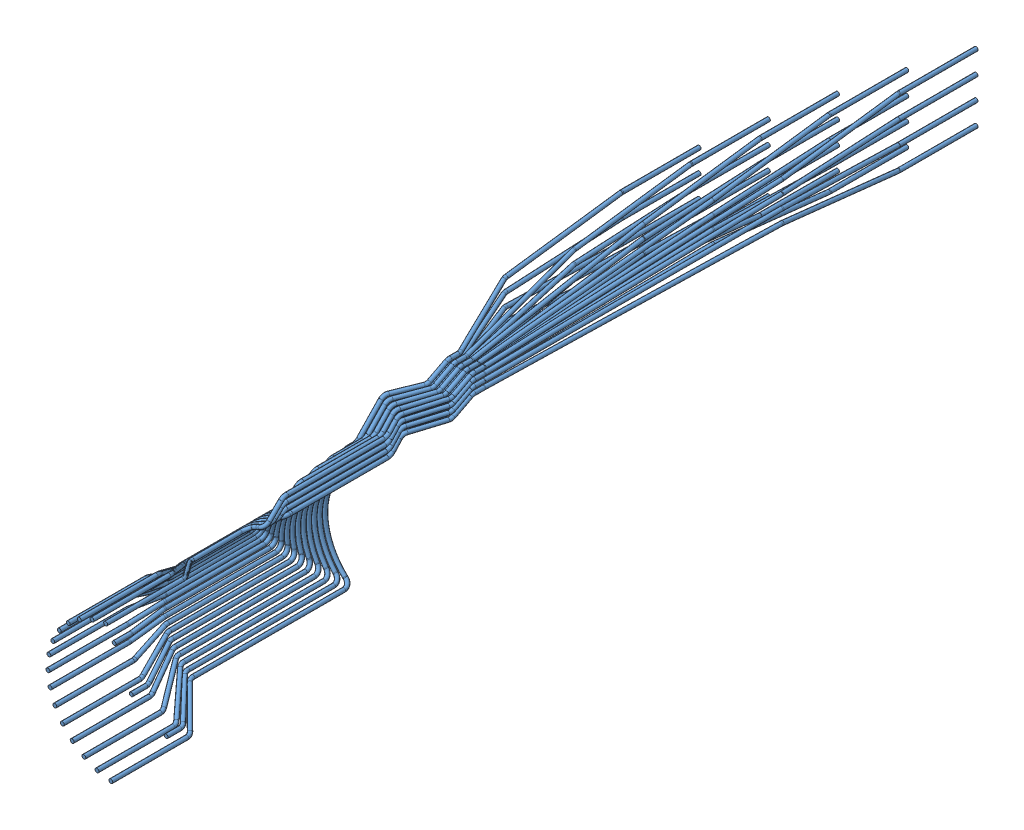
SolidWorks assembly cSLrm, configuration in full west. Lengths in mm.
Overall size (107.53 285.96 1090.7).
40 component instances, 1 part files, 40 mates.
Components (placement in the parent):
- cSLrm1-21: cSLrm1 [11] at origin size (68.98 134.16 1090.7)
- cSLrm1-22: cSLrm1 [12] at origin size (75.18 110.64 1090.7)
- cSLrm1-23: cSLrm1 [13] at origin size (80.86 91.92 1010.4)
- cSLrm1-24: cSLrm1 [14] at origin size (85.95 81.67 1090.7)
- cSLrm1-25: cSLrm1 [21] at origin size (69.41 157.64 1022.7)
- cSLrm1-26: cSLrm1 [22] at origin size (73.2 136.12 1022.7)
- cSLrm1-27: cSLrm1 [23] at origin size (76.27 119.14 942.4)
- cSLrm1-28: cSLrm1 [24] at origin size (80.41 110.37 1022.7)
- cSLrm1-29: cSLrm1 [31] at origin size (64.97 184.68 954.7)
- cSLrm1-30: cSLrm1 [32] at origin size (66.17 171.42 954.7)
- cSLrm1-31: cSLrm1 [33] at origin size (61.36 154.61 874.4)
- cSLrm1-32: cSLrm1 [34] at origin size (63.58 148.57 954.7)
- cSLrm1-33: cSLrm1 [41] at origin size (53.12 229.87 886.7)
- cSLrm1-34: cSLrm1 [42] at origin size (53.16 216.65 886.7)
- cSLrm1-35: cSLrm1 [43] at origin size (53.19 195.57 806.4)
- cSLrm1-16: cSLrm1 [44] at origin size (53.16 188.85 886.7)
- cSLrm1-17: cSLrm1 [51] at origin size (45.95 260.28 818.7)
- cSLrm1-18: cSLrm1 [52] at origin size (62.69 238.45 818.7)
- cSLrm1-19: cSLrm1 [53] at origin size (71.4 211.83 738.4)
- cSLrm1-20: cSLrm1 [54] at origin size (80.51 200.76 818.7)
- cSLrm1-36: cSLrm1 [11fe] at origin (suppressed, hidden)
- cSLrm1-37: cSLrm1 [12fe] at origin (suppressed, hidden)
- cSLrm1-38: cSLrm1 [13fe] at origin (suppressed, hidden)
- cSLrm1-39: cSLrm1 [14fe] at origin (suppressed, hidden)
- cSLrm1-40: cSLrm1 [21fe] at origin (suppressed, hidden)
- cSLrm1-41: cSLrm1 [22fe] at origin (suppressed, hidden)
- cSLrm1-42: cSLrm1 [23fe] at origin (suppressed, hidden)
- cSLrm1-43: cSLrm1 [24fe] at origin (suppressed, hidden)
- cSLrm1-44: cSLrm1 [31fe] at origin (suppressed, hidden)
- cSLrm1-45: cSLrm1 [32fe] at origin (suppressed, hidden)
- cSLrm1-46: cSLrm1 [33fe] at origin (suppressed, hidden)
- cSLrm1-47: cSLrm1 [34fe] at origin (suppressed, hidden)
- cSLrm1-48: cSLrm1 [41fe] at origin (suppressed, hidden)
- cSLrm1-49: cSLrm1 [42fe] at origin (suppressed, hidden)
- cSLrm1-50: cSLrm1 [43fe] at origin (suppressed, hidden)
- cSLrm1-51: cSLrm1 [44fe] at origin (suppressed, hidden)
- cSLrm1-52: cSLrm1 [51fe] at origin (suppressed, hidden)
- cSLrm1-53: cSLrm1 [52fe] at origin (suppressed, hidden)
- cSLrm1-54: cSLrm1 [53fe] at origin (suppressed, hidden)
- cSLrm1-55: cSLrm1 [54fe] at origin (suppressed, hidden)
Mates (geometry in assembly coordinates):
- Coincident1: coordinate: point of ?
- Coincident2: coordinate: unknown of ?
- Coincident3: coordinate: unknown of ?
- Coincident4: coordinate: unknown of ?
- Coincident5: coordinate: unknown of ?
- Coincident6: coordinate: unknown of ?
- Coincident7: coordinate: unknown of ?
- Coincident8: coordinate: unknown of ?
- Coincident9: coordinate: unknown of ?
- Coincident10: coordinate: unknown of ?
- Coincident11: coordinate: unknown of ?
- Coincident12: coordinate: unknown of ?
- Coincident13: coordinate: unknown of ?
- Coincident14: coordinate: unknown of ?
- Coincident15: coordinate: unknown of ?
- Coincident16: coordinate: unknown of ?
- Coincident17: coordinate: unknown of ?
- Coincident18: coordinate: unknown of ?
- Coincident19: coordinate: unknown of ?
- Coincident20: coordinate: unknown of ?
- Coincident21: coordinate: unknown of ?
- Coincident22: coordinate: unknown of ?
- Coincident23: coordinate: unknown of ?
- Coincident24: coordinate: unknown of ?
- Coincident25: coordinate: unknown of ?
- Coincident26: coordinate: unknown of ?
- Coincident27: coordinate: unknown of ?
- Coincident28: coordinate: unknown of ?
- Coincident29: coordinate: unknown of ?
- Coincident30: coordinate: unknown of ?
- Coincident31: coordinate: unknown of ?
- Coincident32: coordinate: unknown of ?
- Coincident33: coordinate: unknown of ?
- Coincident34: coordinate: unknown of ?
- Coincident35: coordinate: unknown of ?
- Coincident36: coordinate: unknown of ?
- Coincident37: coordinate: unknown of ?
- Coincident38: coordinate: unknown of ?
- Coincident39: coordinate: unknown of ?
- Coincident40: coordinate: unknown of ?
